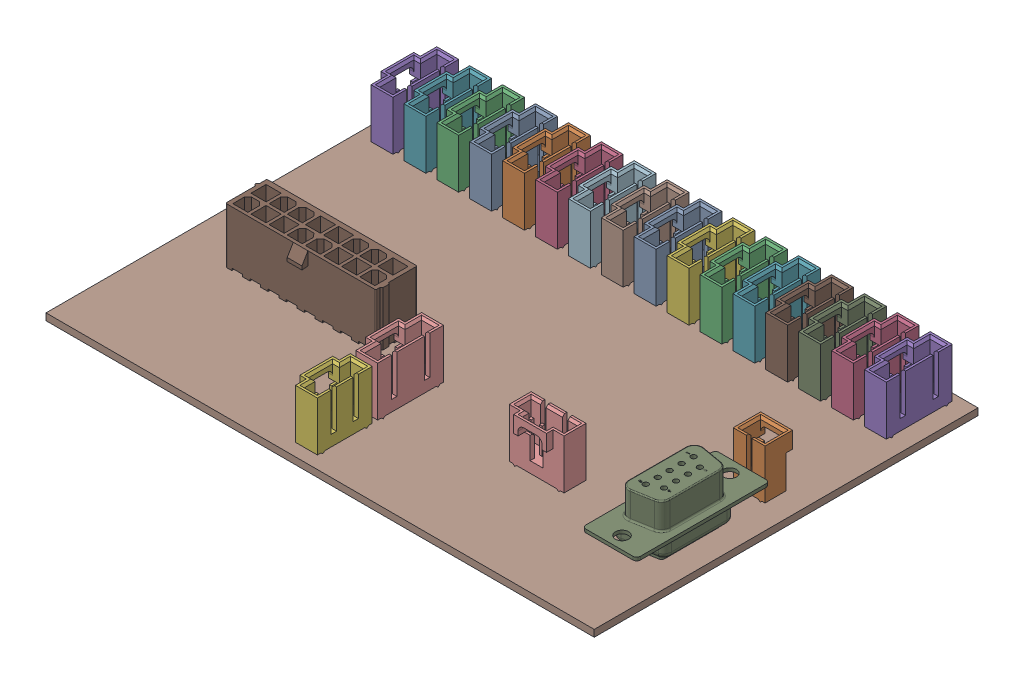
SolidWorks assembly Lithiumate Board Assy, configuration Default. Lengths in mm.
Overall size (127 17.25 88.9).
23 component instances, 6 part files, 0 mates.
Components (placement in the parent):
- Molex 705430004-1: Molex 705430004 [Default] at (-34.417 6.8898 -34.7726) x (0 0 -1) z (0 1 0) size (15.24 6.6 15.11)
- Molex 705430004-2: Molex 705430004 [Default] at (-26.797 6.8898 -34.7726) x (0 0 -1) z (0 1 0) size (15.24 6.6 15.11)
- Molex 705430004-3: Molex 705430004 [Default] at (-42.037 6.8898 -34.7726) x (0 0 -1) z (0 1 0) size (15.24 6.6 15.11)
- Molex 705430004-4: Molex 705430004 [Default] at (49.403 6.8898 -34.7726) x (0 0 -1) z (0 1 0) size (15.24 6.6 15.11)
- Molex 705430004-5: Molex 705430004 [Default] at (-57.277 6.8898 -34.7726) x (0 0 -1) z (0 1 0) size (15.24 6.6 15.11)
- Molex 705430003-1: Molex 705430003 [Default] at (-5.715 6.8898 35.56) x (0 0 -1) z (0 1 0) size (12.7 6.6 15.11)
- Molex 705430004-6: Molex 705430004 [Default] at (-49.657 6.8898 -34.7726) x (0 0 -1) z (0 1 0) size (15.24 6.6 15.11)
- Molex 705430004-7: Molex 705430004 [Default] at (-3.937 6.8898 -34.7726) x (0 0 -1) z (0 1 0) size (15.24 6.6 15.11)
- Molex 705430004-8: Molex 705430004 [Default] at (41.783 6.8898 -34.7726) x (0 0 -1) z (0 1 0) size (15.24 6.6 15.11)
- Molex 705430003-2: Molex 705430003 [Default] at (26.67 6.8898 18.415) x (-1 0 0) z (0 1 0) size (12.7 6.6 15.11)
- Molex 705430004-9: Molex 705430004 [Default] at (34.163 6.8898 -34.7726) x (0 0 -1) z (0 1 0) size (15.24 6.6 15.11)
- Molex 705430004-10: Molex 705430004 [Default] at (-11.557 6.8898 -34.7726) x (0 0 -1) z (0 1 0) size (15.24 6.6 15.11)
- Molex 705430004-11: Molex 705430004 [Default] at (3.683 6.8898 -34.7726) x (0 0 -1) z (0 1 0) size (15.24 6.6 15.11)
- Molex 705430001-1: Molex 705430001 [Default] at (54.6354 6.8898 -2.8448) x (1 0 0) z (0 1 0) size (7.37 6.35 15.11)
- Molex 705430004-12: Molex 705430004 [Default] at (18.923 6.8898 -34.7726) x (0 0 -1) z (0 1 0) size (15.24 6.6 15.11)
- Molex 705430004-13: Molex 705430004 [Default] at (-19.177 6.8898 -34.7726) x (0 0 -1) z (0 1 0) size (15.24 6.6 15.11)
- Molex 705430004-14: Molex 705430004 [Default] at (57.023 6.8898 -34.7726) x (0 0 -1) z (0 1 0) size (15.24 6.6 15.11)
- Molex 705430004-15: Molex 705430004 [Default] at (11.303 6.8898 -34.7726) x (0 0 -1) z (0 1 0) size (15.24 6.6 15.11)
- Molex 705430004-16: Molex 705430004 [Default] at (26.543 6.8898 -34.7726) x (0 0 -1) z (0 1 0) size (15.24 6.6 15.11)
- Lithiumate Board-1: Lithiumate Board [Default] at origin size (127 1.59 88.9)
- NorComp 171-009-213-1: NorComp 171-009-213 [Default] at (61.5696 8.1852 32.6898) x (0 0 -1) z (0 1 0) size (30.81 12.6 17.25)
- Molex 705430004-17: Molex 705430004 [Default] at (-5.715 6.8898 20.32) x (0 0 -1) z (0 1 0) size (15.24 6.6 15.11)
- Molex 039281163-1: Molex 039281163 [Default] at (-34.5176 0.7937 9.6526) size (35.6 16.3 11)
